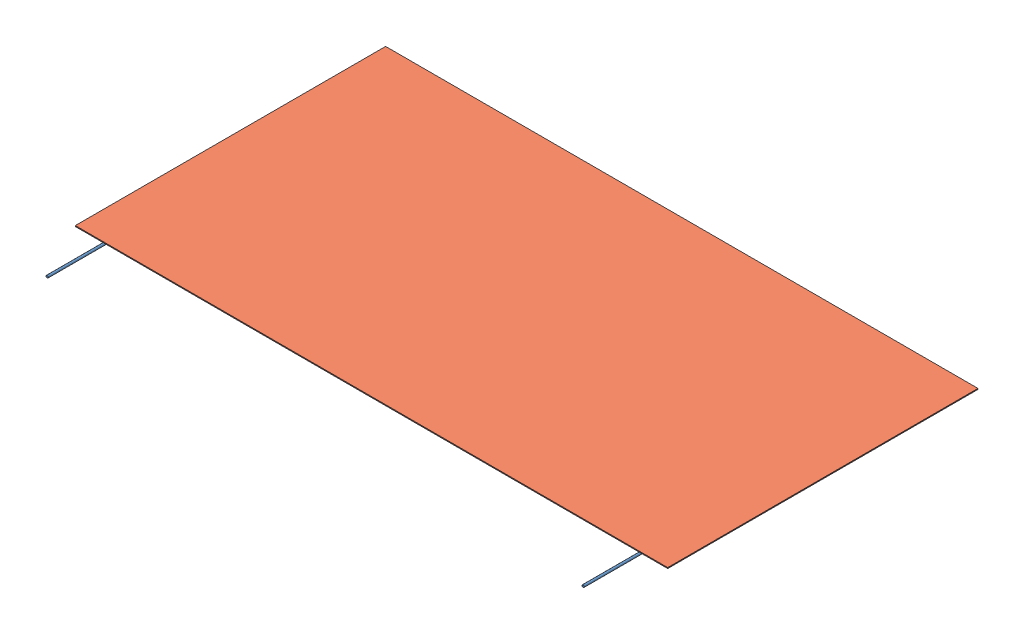
SolidWorks assembly absorber_plate, configuration Default. Lengths in mm.
Overall size (2100 11.11 1300).
2 component instances, 2 part files, 4 mates.
Components (placement in the parent):
- serpentine_manifold-1: serpentine_manifold [Default] at (-0.0012 0 0) size (1907.94 7.94 1253.97)
- absorber-1: absorber [Default] at (-0.0012 3.9688 0) size (2100 3.17 1100)
Mates (geometry in assembly coordinates):
- Tangent2: tangent anti-aligned: cylinder of serpentine_manifold-1 through (-950.0012 0 750) axis (0 0 -1) radius 3.9688; plane of absorber-1 through (-0.0012 3.9688 0) normal (0 -1 0)
- Tangent3: tangent anti-aligned: cylinder of serpentine_manifold-1 through (949.9988 0 -450) axis (0 0 1) radius 3.9688; plane of absorber-1 through (-0.0012 3.9688 0) normal (0 -1 0)
- Symmetric4: symmetric aligned: plane of serpentine_manifold-1 through (-0.0012 0 0) normal (1 0 0); plane of absorber-1 through (-1050.0012 7.1437 -550) normal (-1 0 0); plane of absorber-1 through (1049.9988 7.1437 -550) normal (1 0 0)
- Symmetric5: symmetric aligned: plane of serpentine_manifold-1 through (-0.0012 0 0) normal (0 0 1); plane of absorber-1 through (-1050.0012 7.1437 -550) normal (0 0 -1); plane of absorber-1 through (-1050.0012 7.1437 550) normal (0 0 1)
